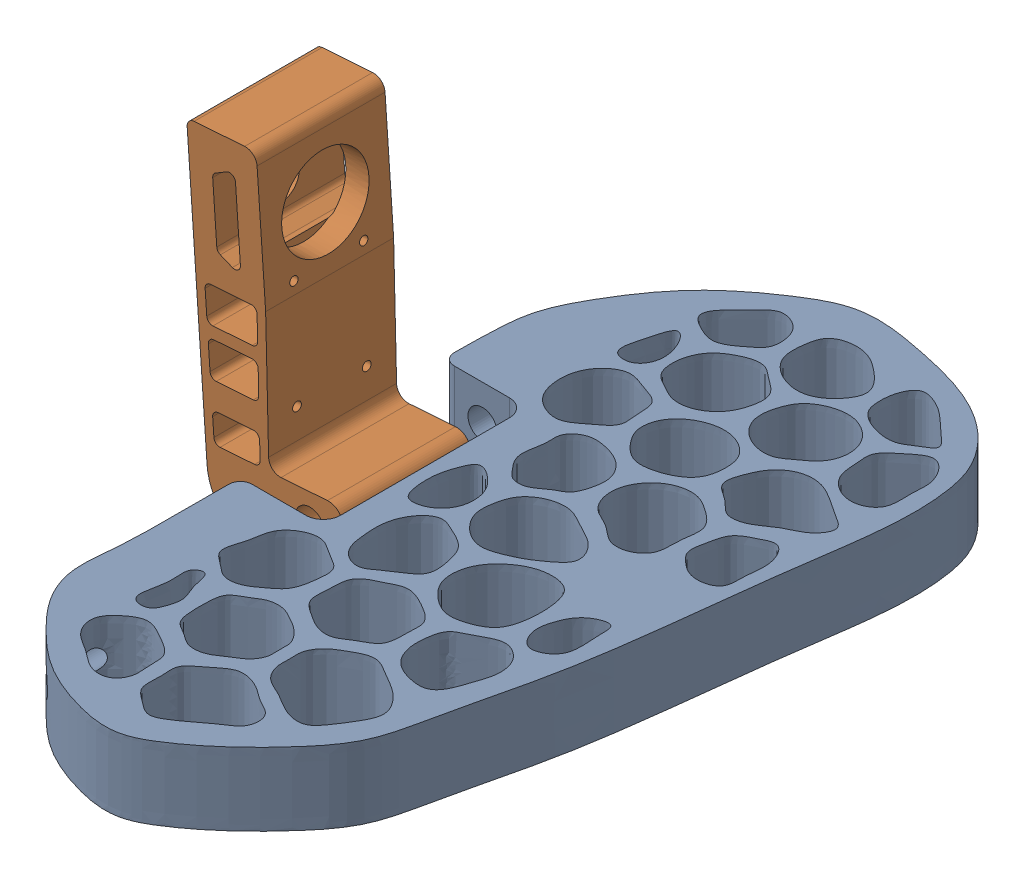
SolidWorks assembly MirrorPedal subassembly, configuration Default. Lengths in mm.
Overall size (157.12 138.3 257.31).
2 component instances, 2 part files, 1 mates.
Components (placement in the parent):
- Mirrornylonove_pedals-1: Mirrornylonove_pedals [Default] at (-15.1911 -18.6389 1.5417) size (130.43 25 257.31)
- Mirrorpedal holder solid-1: Mirrorpedal holder solid [Default] at (-20.4641 -78.6432 73.8896) x (1 0 0) z (0 0.097811 0.995205) size (54.31 133.41 56.48)
Mates (geometry in assembly coordinates):
- Concentric1: concentric anti-aligned: circle of Mirrornylonove_pedals-1; circle of Mirrorpedal holder solid-1
